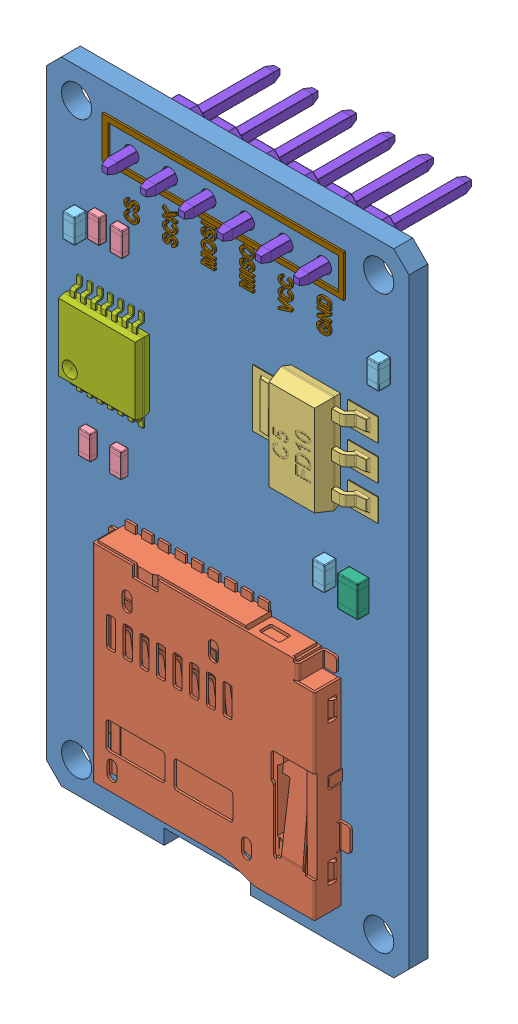
SolidWorks assembly Product_TF Micro SD Card Memory Modul Arduino, configuration Défaut. Lengths in mm.
Overall size (24 41.8 11.46).
20 component instances, 9 part files, 0 mates.
Components (placement in the parent):
- PCB-1: PCB [Défaut] at origin size (24 41.8 1.25)
- slot-1: slot [Défaut] at (-0.1 9.44 2.1) size (16 15 2.44)
- nano - reg-1: nano - reg [Défaut] at (5.85 28.63 1.25) x (0 -1 0) z (-1 0 0) size (6.5 1.69 8.3)
- res_603-1: res_603 [Défaut] at (-9.4 21.6 1.25) x (0 -1 0) z (-1 0 0) size (1.6 0.5 0.8)
- res_603-2: res_603 [Défaut] at (-7.35 21.6 1.25) x (0 -1 0) z (-1 0 0) size (1.6 0.5 0.8)
- res_603-3: res_603 [Défaut] at (-7.3 34.3 1.25) x (0 -1 0) z (-1 0 0) size (1.6 0.5 0.8)
- res_603-4: res_603 [Défaut] at (-8.8 34.3 1.25) x (0 -1 0) z (-1 0 0) size (1.6 0.5 0.8)
- cap_603-1: cap_603 [Défaut] at (-9.34 32.2 2.05) x (0 1 0) z (0 0 1) size (1.6 0.8 0.8)
- cap_603-2: cap_603 [Défaut] at (7.2 20.55 2.05) x (0 1 0) z (0 0 1) size (1.6 0.8 0.8)
- cap_603-3: cap_603 [Défaut] at (10.8 33.9 2.05) x (0 1 0) z (0 0 1) size (1.6 0.8 0.8)
- cap_603_2-1: cap_603_2 [Défaut] at (9.4 20.1 2.05) x (0 1 0) z (0 0 1) size (2.06 1.35 0.82)
- LVC125A-1: LVC125A [Défaut] at (-10.3 28.9 1.25) x (0 -1 0) z (0 0 1) size (6.6 5.2 0.95)
- Pin Header Male 01x06 P2.54mm v1-1: Pin Header Male 01x06 P2.54mm v1 [Défaut] at (6.3487 38.545 -0.0205) x (-1 0 0) z (0 0 -1) size (15.24 2.57 11.39)
  - Male Pin Header_2-1: Male Pin Header_2 [Défaut] at origin size (2.54 2.57 11.39)
  - Male Pin Header_2-2: Male Pin Header_2 [Défaut] at (2.54 0 0) size (2.54 2.57 11.39)
  - Male Pin Header_2-3: Male Pin Header_2 [Défaut] at (5.08 0 0) size (2.54 2.57 11.39)
  - Male Pin Header_2-4: Male Pin Header_2 [Défaut] at (7.62 0 0) size (2.54 2.57 11.39)
  - Male Pin Header_2-5: Male Pin Header_2 [Défaut] at (10.16 0 0) size (2.54 2.57 11.39)
  - Male Pin Header_2-6: Male Pin Header_2 [Défaut] at (12.7 0 0) size (2.54 2.57 11.39)
- Pièce2-1: Pièce2 [Défaut] at (-24.1537 77.863 0.9329) x (0 1 0) z (0 0 1) size (5.42 16 0.14)
